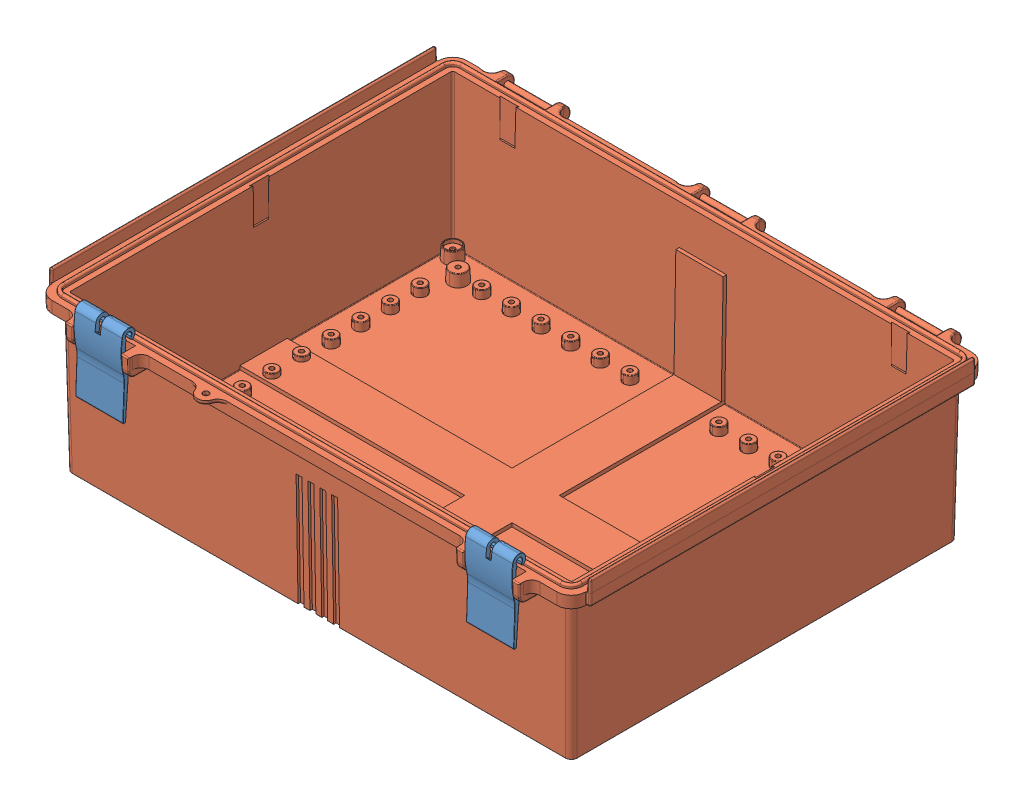
SolidWorks assembly NBF-32028 - Copy, configuration Default. Lengths in mm.
Overall size (457 147.5 373.4).
5 component instances, 3 part files, 0 mates.
Components (placement in the parent):
- NBF-32028.STEP-1: NBF-32028.STEP [Default] at origin size (457 165 374.89)
  - Latch-med-large.STEP-1: Latch-med-large.STEP [Default] at (-164.75 10 178.518) x (-1 0 0) z (0 1 -0.0001) size (40.01 11.7 68)
  - NBF-32028-B.STEP-1: NBF-32028-B.STEP [Default] at origin size (457 142 373.4)
  - NBF-32028-C.STEP-1: NBF-32028-C.STEP [Default] at origin size (450 46.73 374.89) (hidden)
  - Latch-med-large.STEP-2: Latch-med-large.STEP [Default] at (164.75 10 178.518) x (-1 0 0) z (0 1 -0.0001) size (40.01 11.7 68)
